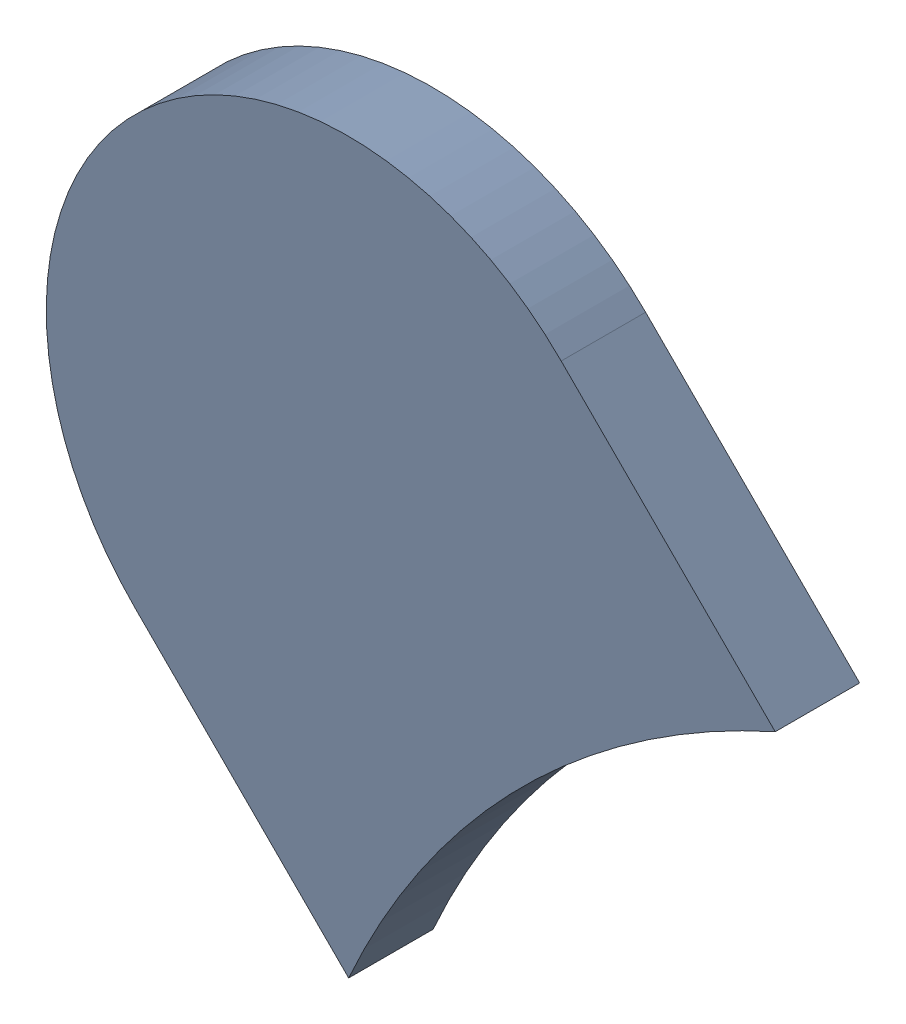
SolidWorks assembly Track (19.975mm,29.725mm)(20.3mm,29.4mm) on Top Layer, configuration Predeterminado. Lengths in mm.
Overall size (0.31 0.31 0.04).
2 component instances, 1 part files, 0 mates.
Components (placement in the parent):
- Track (19.975mm,29.725mm)(20.3mm,29.4mm) on Top Layer-1-1: Track (19.975mm,29.725mm)(20.3mm,29.4mm) on Top Layer-1 [Predeterminado] at (-68.317 -44.187 -0.0457) size (0.31 0.31 0.04)
  - Track (19.975mm,29.725mm)(20.3mm,29.4mm) on Top Layer-Part-1-1: Track (19.975mm,29.725mm)(20.3mm,29.4mm) on Top Layer-Part-1 [Predeterminado] at origin size (0.31 0.31 0.04)
